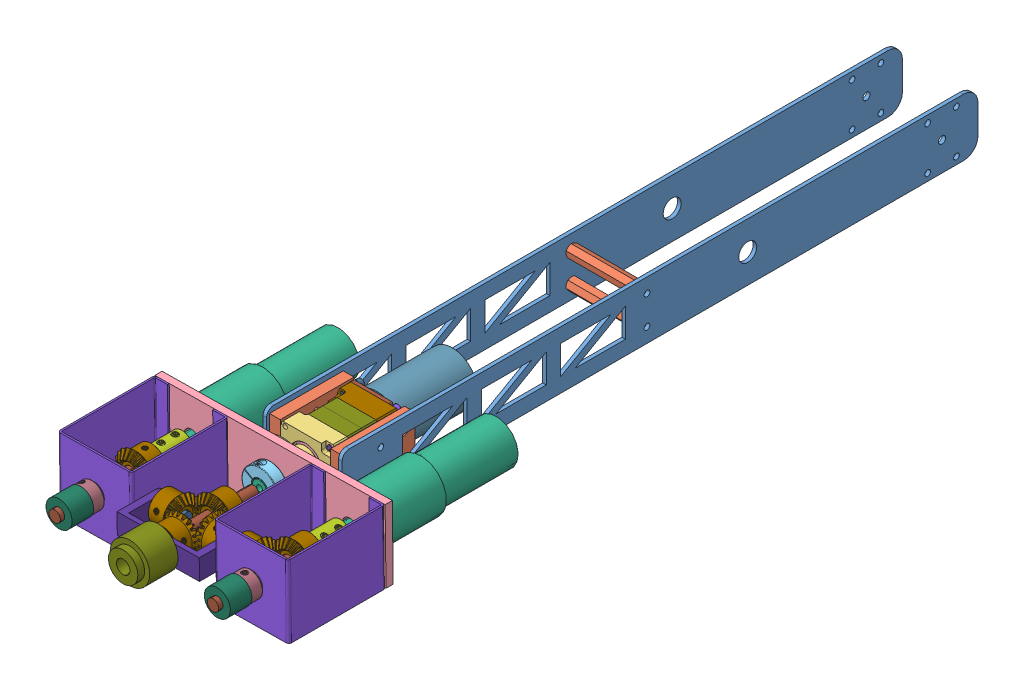
SolidWorks assembly Wrist, configuration Default. Lengths in mm.
Overall size (204.05 66.26 719.42).
77 component instances, 35 part files, 98 mates.
Components (placement in the parent):
- Arm_Plate-1: Arm_Plate [Default] at (186.0926 430.0867 393.4648) size (3.17 50.8 561.12)
- Arm_Plate-2: Arm_Plate [Default] at (252.7676 430.0867 393.4648) size (3.17 50.8 561.12)
- Beta_Standoff-1: Beta_Standoff [91115A862] at (221.0176 442.7867 507.7648) x (0 -0.986565 -0.163369) z (-1 0 0) size (9.53 11 64.12)
- Beta_Standoff-2: Beta_Standoff [91115A862] at (221.0176 468.1867 507.7648) x (0 0.925164 -0.379567) z (-1 0 0) size (9.53 11 64.12)
- Gearbox-1: Gearbox [Default] at (243.2426 455.4867 757.6023) x (0 0 1) z (0 -1 0) size (107.66 49.05 49.3)
  - 217-2625-026 Rev1-1: 217-2625-026 Rev1 [Default] at (-6.5 22.225 0) x (0 -1 0) z (-1 0 0) size (44.45 42 18.13)
  - 217-2742-001 Rev4-1: 217-2742-001 Rev4 [Default] at (0.2002 22.225 0) x (1 0 0) z (0 -0.092627 0.995701) size (7 28 28)
  - 217-2742-001 Rev4-2: 217-2742-001 Rev4 [Default] at (8.2002 22.225 0) size (7 28 28)
  - 217-2625-017 Rev1_9714K61-1: 217-2625-017 Rev1_9714K61 [Default] at (7.42 22.3002 -0.342) x (0 0.56703 0.823697) z (0 -0.823697 0.56703) size (28.51 4.98 30.18)
  - 217-2625-003 Rev1-1: 217-2625-003 Rev1 [Default] at (7.4478 22.225 0) x (0 -1 0) z (1 0 0) size (17 17 64.12)
  - 217-2625-018 Rev1_98541A410-1: 217-2625-018 Rev1_98541A410 [Default] at (-0.7046 22.225 0) x (1 0 0) z (0 -0.017452 0.999848) size (1 19.6 17.4)
  - 832-2250-Base-Kit-Screw_SSA0832-0500ZC-1: 832-2250-Base-Kit-Screw_SSA0832-0500ZC [Default] at (-43.4 4.725 -17.5) x (0 -0.767799 -0.640691) z (0 0.640691 -0.767799) size (6.73 61.21 6.73)
  - 832-2250-Base-Kit-Screw_SSA0832-0500ZC-2: 832-2250-Base-Kit-Screw_SSA0832-0500ZC [Default] at (-43.4 39.725 17.5) x (0 0.961307 0.275478) z (0 -0.275478 0.961307) size (6.73 61.21 6.73)
  - 217-2625-025 Rev1-1: 217-2625-025 Rev1 [Default] at (-35.9 22.225 0) x (0 -1 0) z (-1 0 0) size (44.45 42 18)
  - 217-4649-002 Rev1_SSA0832-0500ZC-1: 217-4649-002 Rev1_SSA0832-0500ZC [Default] at (-46.4 4.2645 17.9605) x (0 0.33842 -0.940995) z (0 0.940995 0.33842) size (6.73 16.76 6.73)
  - 217-4649-002 Rev1_SSA0832-0500ZC-2: 217-4649-002 Rev1_SSA0832-0500ZC [Default] at (-46.4 40.1855 -17.9605) x (0 -0.308932 -0.951084) z (0 0.951084 -0.308932) size (6.73 16.76 6.73)
  - 217-2822-003 Rev4-1: 217-2822-003 Rev4 [Default] at (-44.9 22.225 0) x (0 -1 0) z (-1 0 0) size (42 42 4.8)
  - 217-2820 Rev1_Public-1: 217-2820 Rev1_Public [Default] at (-4.6546 22.225 0) x (0 -0.456494 0.889726) z (-1 0 0) size (39.26 38.9 17.4)
    - 217-2625-100-1: 217-2625-100 [Default] at origin size (39.26 38.9 12.7)
      - 217-2625-008 Rev1-1: 217-2625-008 Rev1 [Default] at origin size (34.7 34.7 4.7)
      - 217-2625-010 Rev1-1: 217-2625-010 Rev1 [Default] at (0 10.193 3.65) x (0.999813 0.019336 0) z (0 0 1) size (4 4 12)
      - 217-2625-010 Rev1-2: 217-2625-010 Rev1 [Default] at (8.691 -5.3258 3.65) size (4 4 12)
      - 217-2625-010 Rev1-3: 217-2625-010 Rev1 [Default] at (-8.691 -5.3258 3.65) size (4 4 12)
      - 217-2625-005 Rev1_Planet_Revolving_Follower01-1: 217-2625-005 Rev1_Planet_Revolving_Follower01 [Default] at (8.691 -5.3258 6.35) x (0.932816 0.360354 0) z (0 0 1) size (16.91 16.92 8)
      - 217-2625-005 Rev1_Planet_Revolving_Follower01-2: 217-2625-005 Rev1_Planet_Revolving_Follower01 [Default] at (-8.691 -5.3258 6.35) x (-0.932788 -0.360426 0) z (0 0 1) size (16.91 16.92 8)
      - 217-2625-005 Rev1_Planet_Revolving_Follower01-3: 217-2625-005 Rev1_Planet_Revolving_Follower01 [Default] at (0 10.193 6.35) x (0.893583 0.448898 0) z (0 0 1) size (16.91 16.92 8)
    - 217-2625-007 Rev1_Public-1: 217-2625-007 Rev1_Public [Default] at (0 0 6.7) x (0.992772 0.120019 0) z (0 0 1) size (14.49 14.49 12.72)
  - 217-2816-001 Rev1-1: 217-2816-001 Rev1 [Default] at (-6.35 22.225 0) x (0 -1 0) z (1 0 0) size (42 42 14.5)
  - 217-2820 Rev1_Public-2: 217-2820 Rev1_Public [Default] at (-17.15 22.225 0) x (0 0.184082 0.982911) z (-1 0 0) size (39.26 38.9 17.4)
    - 217-2625-100-1: 217-2625-100 [Default] at origin size (39.26 38.9 12.7)
      - 217-2625-008 Rev1-1: 217-2625-008 Rev1 [Default] at origin size (34.7 34.7 4.7)
      - 217-2625-010 Rev1-1: 217-2625-010 Rev1 [Default] at (0 10.193 3.65) x (0.999813 0.019336 0) z (0 0 1) size (4 4 12)
      - 217-2625-010 Rev1-2: 217-2625-010 Rev1 [Default] at (8.691 -5.3258 3.65) size (4 4 12)
      - 217-2625-010 Rev1-3: 217-2625-010 Rev1 [Default] at (-8.691 -5.3258 3.65) size (4 4 12)
      - 217-2625-005 Rev1_Planet_Revolving_Follower01-1: 217-2625-005 Rev1_Planet_Revolving_Follower01 [Default] at (8.691 -5.3258 6.35) x (0.932816 0.360354 0) z (0 0 1) size (16.91 16.92 8)
      - 217-2625-005 Rev1_Planet_Revolving_Follower01-2: 217-2625-005 Rev1_Planet_Revolving_Follower01 [Default] at (-8.691 -5.3258 6.35) x (-0.932788 -0.360426 0) z (0 0 1) size (16.91 16.92 8)
      - 217-2625-005 Rev1_Planet_Revolving_Follower01-3: 217-2625-005 Rev1_Planet_Revolving_Follower01 [Default] at (0 10.193 6.35) x (0.893583 0.448898 0) z (0 0 1) size (16.91 16.92 8)
    - 217-2625-007 Rev1_Public-1: 217-2625-007 Rev1_Public [Default] at (0 0 6.7) x (0.992772 0.120019 0) z (0 0 1) size (14.49 14.49 12.72)
  - 217-2816-001 Rev1-2: 217-2816-001 Rev1 [Default] at (-19.05 22.225 0) x (0 -1 0) z (1 0 0) size (42 42 14.5)
  - 217-4649-001 Rev1-1: 217-4649-001 Rev1 [Default] at (-32.746 22.225 0) x (0 -1 0) z (1 0 0) size (18 18 13)
  - 217-4649-007 Rev1_94105A824-1: 217-4649-007 Rev1_94105A824 [Default] at (-38.221 22.225 -6.7835) x (-0.996104 -0.088191 0) z (0 0 -1) size (4.83 4.83 4.9)
  - 217-2625-011 Rev1-1: 217-2625-011 Rev1 [Default] at (-37.4818 22.225 0) x (0 0 1) z (0 -1 0) size (8.01 7.5 7.94)
- Standoff_Plate-1: Standoff_Plate [Default] at (198.7926 476.4867 709.1173) x (0 0 -1) z (0 1 0) size (65.11 9.53 42)
- Standoff_Plate-2: Standoff_Plate [Default] at (243.2426 434.4867 709.1173) x (0 0 -1) z (0 -1 0) size (65.11 9.53 42)
- Hex_Hub-1: Hex_Hub [Default] at (220.9668 455.4867 780.2423) x (0 0 -1) z (-1 0 0) size (25.4 57.15 57.15)
- Fork-2: Fork [Default] at (119.8085 422.3563 805.0883) x (-0.999907 -0.013615 0) z (0.013615 -0.999907 0) size (203.2 6.35 63.5)
- Hex_Collar-1: Hex_Collar [7552K5] at (220.9668 455.4867 809.8508) x (-0.5 -0.866025 0) z (0 0 -1) size (31.75 31.77 10.99)
- PG71-3: PG71 [Default] at (151.1233 454.5357 742.2233) x (0.829348 0.558732 0) z (0.558732 -0.829348 0) size (45.01 149.99 45.01)
- PG71-4: PG71 [Default] at (290.8104 456.4377 742.2233) x (0.30986 0.950782 0) z (0.950782 -0.30986 0) size (45.01 149.99 45.01)
- 10mm_Coupler-1: 10mm_Coupler [5395T312] at (290.8104 456.4377 825.6623) x (0.860413 -0.509597 0) z (0 0 1) size (19 20.01 25.02)
- 10mm_Coupler-2: 10mm_Coupler [5395T312] at (151.1233 454.5357 825.6623) size (19 20.01 25.02)
- Differential_Plate-3: Differential_Plate [Default] at (259.2456 424.2549 806.6758) x (-0.999907 -0.013615 0) z (-0.013615 0.999907 0) size (65.34 85.73 63.5)
- Differential_Plate-4: Differential_Plate [Default] at (182.6881 486.7184 806.6758) x (0.999907 0.013615 0) z (0.013615 -0.999907 0) size (65.34 85.73 63.5)
- Miter-7: Miter [2600N3] at (151.1233 454.5357 855.0883) x (-0.049068 -0.998795 0) z (-0.998795 0.049068 0) size (31.74 21.31 31.74)
- Miter-8: Miter [2600N3] at (290.8104 456.4377 855.0883) x (0.920442 -0.390878 0) z (-0.390878 -0.920442 0) size (31.74 21.31 31.74)
- Miter-9: Miter [2600N3] at (166.1219 454.7399 870.0883) x (-0.002712 0.199199 -0.979955) z (-0.013342 0.979865 0.199217) size (31.74 21.31 31.74)
- Miter-10: Miter [2600N3] at (275.8117 456.2335 870.0883) x (0.010216 -0.750274 -0.661048) z (0.009 -0.660987 0.750343) size (31.74 21.31 31.74)
- 10mm_Shaft-7: 10mm_Shaft [Default] at (212.1176 455.3662 870.0883) x (-0.001745 0.128178 -0.99175) z (-0.013503 0.991658 0.12819) size (10 50 10)
- 10mm_Shaft-8: 10mm_Shaft [Default] at (279.8114 456.2879 870.0883) x (0.007901 -0.580251 -0.814399) z (-0.011088 0.814324 -0.580305) size (10 50 10)
- Miter-11: Miter [2600N3] at (235.9654 455.6909 870.0883) x (0.012189 -0.895158 -0.445582) z (-0.006067 0.44554 -0.895241) size (31.74 21.31 31.74)
- Miter-12: Miter [2600N3] at (205.9682 455.2824 870.0883) x (0.00474 -0.348103 -0.937444) z (0.012763 -0.937358 0.348135) size (31.74 21.31 31.74)
- Pitch_Shaft-10: Pitch_Shaft [Default] at (290.8104 456.4377 925.6623) x (-0.350616 -0.936519 0) z (0.936519 -0.350616 0) size (10 100 10)
- 10mm_Bearing-1: 10mm_Bearing [Default] at (290.8104 456.4377 892.8133) x (-0.923728 -0.383049 0) z (0.383049 -0.923728 0) size (18 8 18)
- 10mm_Collar-1: 10mm_Collar [57485K68] at (290.8104 456.4377 892.8133) size (22 22 10)
- Pitch_Shaft-11: Pitch_Shaft [Default] at (151.1233 454.5357 925.6623) x (-0.160979 -0.986958 0) z (0.986958 -0.160979 0) size (10 100 10)
- 10mm_Bearing-2: 10mm_Bearing [Default] at (151.1233 454.5357 892.8133) x (-0.561775 -0.82729 0) z (0.82729 -0.561775 0) size (18 8 18)
- 10mm_Collar-2: 10mm_Collar [57485K68] at (151.1233 454.5357 892.8133) x (0.924433 0.381344 0) z (0 0 1) size (22 22 10)
- 10mm_Bearing-3: 10mm_Bearing [Default] at (260.8131 456.0292 870.0883) x (0.013072 -0.960036 0.279573) z (0.003806 -0.279547 -0.960124) size (18 8 18)
- 10mm_Bearing-4: 10mm_Bearing [Default] at (181.1205 454.9441 870.0883) x (0.002168 -0.159219 0.987241) z (-0.013441 0.987149 0.159233) size (18 8 18)
- Pitch_Shaft-14: Pitch_Shaft [Default] at (220.9668 455.4867 920.0883) x (0.474138 -0.880451 0) z (0.880451 0.474138 0) size (10 100 10)
- Miter-19: Miter [2600N3] at (220.9668 455.4867 885.0883) x (-0.926792 -0.375575 0) z (0.375575 -0.926792 0) size (31.74 21.31 31.74)
- Miter-20: Miter [2600N3] at (220.9668 455.4867 855.0883) x (-0.987805 -0.155698 0) z (-0.155698 0.987805 0) size (31.74 21.31 31.74)
- 9015_Motor-1: 9015_Motor [Default] at (221.0176 455.4867 711.2023) x (0.980858 0.194723 0) z (-0.194723 0.980858 0) size (44.5 66.55 44.5)
- Encoder-1: Encoder [Default] at (290.8104 456.4377 902.8133) x (0.92907 -0.369904 0) z (-0.369904 -0.92907 0) size (23 19 23)
- Encoder-2: Encoder [Default] at (151.1233 454.5357 902.8133) x (0.974433 -0.224677 0) z (-0.224677 -0.974433 0) size (23 19 23)
- Slip_Ring-2: Slip_Ring [Default] at (220.9668 455.4867 904.0883) x (-0.999021 -0.044228 0) z (-0.044228 0.999021 0) size (35 31 35)
- Differential_Cover-1: Differential_Cover [Default] at (190.9696 455.0782 870.0883) x (-0.999907 -0.013615 0) z (0.013615 -0.999907 0) size (72.52 43 18)
Mates (geometry in assembly coordinates):
- Coincident1: coincident anti-aligned: plane of Arm_Plate-1 through (189.2676 442.7867 228.3648) normal (1 0 0); plane of Beta_Standoff-1 through (189.2676 441.8883 513.1902) normal (-1 0 0)
- Coincident2: coincident anti-aligned: plane of Arm_Plate-2 through (252.7676 442.7867 228.3648) normal (-1 0 0); plane of Beta_Standoff-1 through (252.7676 441.8883 513.1902) normal (1 0 0)
- Concentric1: concentric aligned: circle of Arm_Plate-1; circle of Beta_Standoff-1
- Concentric2: concentric aligned: circle of Arm_Plate-1; circle of Arm_Plate-2
- Concentric3: concentric aligned: circle of Arm_Plate-1; circle of Beta_Standoff-2
- Coincident4: coincident anti-aligned: plane of Arm_Plate-1 through (189.2676 442.7867 228.3648) normal (1 0 0); plane of Beta_Standoff-2 through (189.2676 466.0994 502.6771) normal (-1 0 0)
- Parallel1: parallel anti-aligned: plane of Arm_Plate-2 through (255.9426 442.7867 228.3648) normal (1 0 0); plane of Gearbox-1/217-2816-001 Rev1-1 through (200.0176 434.4867 757.6023) normal (-1 0 0)
- Parallel2: parallel aligned: plane of Arm_Plate-2 through (255.9426 480.8867 228.3648) normal (0 1 0); plane of Gearbox-1/217-2625-026 Rev1-1 through (242.0176 476.4867 756.1023) normal (0 1 0)
- Width2: width anti-aligned: plane of Arm_Plate-2 through (255.9426 442.7867 228.3648) normal (1 0 0); plane of Arm_Plate-1 through (186.0926 442.7867 228.3648) normal (-1 0 0); plane of Gearbox-1/217-2816-001 Rev1-1 through (200.0176 434.4867 757.6023) normal (-1 0 0); plane of Gearbox-1/217-2816-001 Rev1-1 through (242.0176 434.4867 757.6023) normal (1 0 0)
- Width3: width anti-aligned: plane of Arm_Plate-2 through (255.9426 480.8867 228.3648) normal (0 1 0); plane of Arm_Plate-2 through (255.9426 430.0867 228.3648) normal (0 -1 0); plane of Gearbox-1/217-2816-001 Rev1-2 through (200.0176 434.4867 744.9023) normal (0 -1 0); plane of Gearbox-1/217-2816-001 Rev1-2 through (200.0176 476.4867 744.9023) normal (0 1 0)
- Concentric4: concentric aligned: circle of Arm_Plate-1; circle of Arm_Plate-2
- Width4: width: plane of Gearbox-1/217-2822-003 Rev4-1 through (221.0176 455.4867 711.2023) normal (0 0 -1); plane of Gearbox-1/217-2625-026 Rev1-1 through (198.7926 433.2617 774.2273) normal (0 0 1); cylinder of Arm_Plate-2 through (255.9426 442.7867 742.7148) axis (-1 0 0) radius 2.5527
- Coincident9: coincident anti-aligned: plane of Gearbox-1/217-2625-026 Rev1-1 through (198.7926 477.7117 774.2273) normal (-1 0 0); plane of Standoff_Plate-1 through (198.7926 476.4867 709.1173) normal (1 0 0)
- Coincident10: coincident aligned: plane of Gearbox-1/217-2625-026 Rev1-1 through (198.7926 433.2617 774.2273) normal (0 0 1); plane of Standoff_Plate-1 through (189.2676 476.4867 774.2273) normal (0 0 1)
- Coincident11: coincident aligned: plane of Gearbox-1/217-2625-026 Rev1-1 through (242.0176 434.4867 756.1023) normal (0 -1 0); plane of Standoff_Plate-1 through (189.2676 434.4867 709.1173) normal (0 -1 0)
- Coincident12: coincident anti-aligned: plane of Gearbox-1/217-2625-026 Rev1-1 through (243.2426 477.7117 774.2273) normal (1 0 0); plane of Standoff_Plate-2 through (243.2426 434.4867 709.1173) normal (-1 0 0)
- Coincident14: coincident aligned: plane of Gearbox-1/217-2625-026 Rev1-1 through (198.7926 433.2617 774.2273) normal (0 0 1); plane of Standoff_Plate-2 through (252.7676 434.4867 774.2273) normal (0 0 1)
- Coincident15: coincident aligned: plane of Gearbox-1/217-2625-026 Rev1-1 through (242.0176 476.4867 756.1023) normal (0 1 0); plane of Standoff_Plate-2 through (252.7676 476.4867 709.1173) normal (0 1 0)
- Coincident16: coincident anti-aligned: plane of Gearbox-1/217-2625-003 Rev1-1 through (221.0176 448.1543 814.8025) normal (0.5 -0.866025 0); plane of Hex_Hub-1 through (220.9668 448.125 774.2273) normal (-0.5 0.866025 0)
- Coincident17: coincident anti-aligned: plane of Gearbox-1/217-2625-026 Rev1-1 through (198.7926 433.2617 774.2273) normal (0 0 1); plane of Hex_Hub-1 through (220.9668 455.4867 774.2273) normal (0 0 -1)
- Coincident18: coincident anti-aligned: plane of Gearbox-1/217-2625-003 Rev1-1 through (227.3676 459.1529 814.8025) normal (0.5 0.866025 0); plane of Hex_Hub-1 through (227.3422 459.1675 774.2273) normal (-0.5 -0.866025 0)
- Coincident21: coincident anti-aligned: plane of Hex_Hub-1 through (220.9668 455.4867 798.7383) normal (0 0 1); plane of Fork-2 through (119.8085 422.3563 798.7383) normal (0 0 -1)
- Concentric7: concentric aligned: circle of Hex_Hub-1; cylinder of Fork-2 through (220.9668 455.4867 805.0883) axis (0 0 -1) radius 6.35
- Coincident22: coincident anti-aligned: plane of Fork-2 through (119.8085 422.3563 805.0883) normal (0 0 1); plane of Hex_Collar-1 through (220.9668 455.4867 805.0883) normal (0 0 -1)
- Concentric8: concentric aligned: cylinder of Hex_Hub-1 through (220.9668 455.4867 774.2273) axis (0 0 1) radius 12.1666; cylinder of Hex_Collar-1 through (220.9668 455.4867 805.0883) axis (0 0 1) radius 15.875
- Parallel4: parallel anti-aligned: plane of Gearbox-1/217-2625-003 Rev1-1 through (214.6676 451.8205 814.8025) normal (-0.5 -0.866025 0); plane of Hex_Collar-1 through (220.9668 448.1543 805.0883) normal (0.5 0.866025 0)
- Coincident25: coincident anti-aligned: plane of Fork-2 through (119.8085 422.3563 798.7383) normal (0 0 -1); plane of PG71-3 through (151.1233 454.5357 798.7383) normal (0 0 1)
- Coincident26: coincident anti-aligned: plane of Fork-2 through (119.8085 422.3563 798.7383) normal (0 0 -1); plane of PG71-4 through (290.8104 456.4377 798.7383) normal (0 0 1)
- Concentric10: concentric aligned: cylinder of Fork-2 through (151.1233 454.5357 805.0883) axis (0 0 -1) radius 6.35; cylinder of PG71-3 through (151.1233 454.5357 825.6623) axis (0 0 -1) radius 5
- Concentric11: concentric aligned: cylinder of Fork-2 through (290.8104 456.4377 805.0883) axis (0 0 -1) radius 6.35; cylinder of PG71-4 through (290.8104 456.4377 825.6623) axis (0 0 -1) radius 5
- Concentric25: concentric aligned: cylinder of PG71-4 through (290.8104 456.4377 825.6623) axis (0 0 -1) radius 5; cylinder of 10mm_Coupler-1 through (290.8104 456.4377 838.1623) axis (0 0 -1) radius 5
- Concentric26: concentric aligned: cylinder of PG71-3 through (151.1233 454.5357 825.6623) axis (0 0 -1) radius 5; cylinder of 10mm_Coupler-2 through (151.1233 454.5357 838.1623) axis (0 0 -1) radius 5
- Distance7: distance = 12.5 mm aligned: plane of 10mm_Coupler-1 through (290.8104 456.4377 838.1623) normal (0 0 1); plane of PG71-4 through (290.8104 456.4377 825.6623) normal (0 0 1)
- Distance8: distance = 12.5 mm aligned: plane of 10mm_Coupler-2 through (151.1233 454.5357 838.1623) normal (0 0 1); plane of PG71-3 through (151.1233 454.5357 825.6623) normal (0 0 1)
- Coincident41: coincident anti-aligned: plane of Fork-2 through (119.8085 422.3563 805.0883) normal (0 0 1); plane of Differential_Plate-3 through (259.2456 424.2549 805.0883) normal (0 0 -1)
- Coincident42: coincident anti-aligned: plane of Fork-2 through (119.8085 422.3563 805.0883) normal (0 0 1); plane of Differential_Plate-4 through (182.6881 486.7184 805.0883) normal (0 0 -1)
- Parallel9: parallel anti-aligned: plane of Fork-2 through (119.8085 422.3563 798.7383) normal (-0.999907 -0.013615 0); plane of Differential_Plate-3 through (258.381 487.7491 806.6758) normal (0.999907 0.013615 0)
- Parallel10: parallel aligned: plane of Fork-2 through (119.8085 422.3563 798.7383) normal (-0.999907 -0.013615 0); plane of Differential_Plate-4 through (183.5526 423.2243 806.6758) normal (-0.999907 -0.013615 0)
- Coincident43: coincident aligned: plane of Fork-2 through (119.8085 422.3563 798.7383) normal (0.013615 -0.999907 0); plane of Differential_Plate-4 through (172.4411 423.073 805.0883) normal (0.013615 -0.999907 0)
- Coincident44: coincident aligned: plane of Fork-2 through (119.8085 422.3563 798.7383) normal (0.013615 -0.999907 0); plane of Differential_Plate-3 through (259.2456 424.2549 805.0883) normal (0.013615 -0.999907 0)
- Distance11: distance = 35 mm anti-aligned: plane of Miter-7 through (151.1233 454.5357 840.0883) normal (0 0 -1); plane of Fork-2 through (119.8085 422.3563 805.0883) normal (0 0 1)
- Distance12: distance = 35 mm anti-aligned: plane of Miter-8 through (290.8104 456.4377 840.0883) normal (0 0 -1); plane of Fork-2 through (119.8085 422.3563 805.0883) normal (0 0 1)
- Concentric33: concentric aligned: circle of Differential_Plate-4; cylinder of Miter-9 through (146.5963 454.474 870.0883) axis (-0.999907 -0.013615 0) radius 5
- Concentric34: concentric aligned: circle of Differential_Plate-3; cylinder of Miter-10 through (295.3374 456.4993 870.0883) axis (0.999907 0.013615 0) radius 5
- GearMate5: gear = 26 : 26 mm: cylinder of Miter-7 through (151.1233 454.5357 871.5883) axis (0 0 -1) radius 13; cylinder of Miter-9 through (149.6234 454.5152 870.0883) axis (0.999907 0.013615 0) radius 13
- GearMate6: gear = 26 : 26 mm: cylinder of Miter-10 through (292.3102 456.4581 870.0883) axis (-0.999907 -0.013615 0) radius 13; cylinder of Miter-8 through (290.8104 456.4377 871.5883) axis (0 0 -1) radius 13
- Concentric35: concentric anti-aligned: cylinder of Miter-9 through (146.5963 454.474 870.0883) axis (-0.999907 -0.013615 0) radius 5; cylinder of 10mm_Shaft-7 through (162.1223 454.6854 870.0883) axis (0.999907 0.013615 0) radius 5
- Concentric36: concentric aligned: cylinder of Miter-10 through (295.3374 456.4993 870.0883) axis (0.999907 0.013615 0) radius 5; cylinder of 10mm_Shaft-8 through (229.816 455.6072 870.0883) axis (0.999907 0.013615 0) radius 5
- Coincident47: coincident aligned: plane of Miter-10 through (279.8114 456.2879 870.0883) normal (0.999907 0.013615 0); plane of 10mm_Shaft-8 through (279.8114 456.2879 870.0883) normal (0.999907 0.013615 0)
- Coincident48: coincident aligned: plane of Miter-9 through (162.1223 454.6854 870.0883) normal (-0.999907 -0.013615 0); plane of 10mm_Shaft-7 through (162.1223 454.6854 870.0883) normal (-0.999907 -0.013615 0)
- Concentric37: concentric aligned: cylinder of 10mm_Shaft-7 through (162.1223 454.6854 870.0883) axis (0.999907 0.013615 0) radius 5; cylinder of Miter-12 through (225.4939 455.5483 870.0883) axis (0.999907 0.013615 0) radius 5
- Concentric38: concentric anti-aligned: cylinder of 10mm_Shaft-8 through (229.816 455.6072 870.0883) axis (0.999907 0.013615 0) radius 5; cylinder of Miter-11 through (216.4398 455.425 870.0883) axis (-0.999907 -0.013615 0) radius 5
- Distance13: distance = 60 mm anti-aligned: plane of Miter-12 through (190.9696 455.0782 870.0883) normal (-0.999907 -0.013615 0); plane of Miter-11 through (250.964 455.8951 870.0883) normal (0.999907 0.013615 0)
- Width10: width aligned: plane of Differential_Plate-4 through (185.14 423.2459 806.6758) normal (0.999907 0.013615 0); plane of Differential_Plate-3 through (256.7937 487.7274 806.6758) normal (-0.999907 -0.013615 0); plane of Miter-11 through (250.964 455.8951 870.0883) normal (0.999907 0.013615 0); plane of Miter-12 through (190.9696 455.0782 870.0883) normal (-0.999907 -0.013615 0)
- GearMate7: gear = 26 : 26 mm: cylinder of Miter-12 through (222.4667 455.5071 870.0883) axis (-0.999907 -0.013615 0) radius 13; cylinder of Miter-9 through (149.6234 454.5152 870.0883) axis (0.999907 0.013615 0) radius 13
- GearMate8: gear = 26 : 26 mm: cylinder of Miter-11 through (219.467 455.4662 870.0883) axis (0.999907 0.013615 0) radius 13; cylinder of Miter-10 through (292.3102 456.4581 870.0883) axis (-0.999907 -0.013615 0) radius 13
- Concentric39: concentric anti-aligned: cylinder of 10mm_Coupler-1 through (290.8104 456.4377 838.1623) axis (0 0 -1) radius 5; cylinder of Miter-8 through (290.8104 456.4377 874.6158) axis (0 0 1) radius 5
- Concentric40: concentric anti-aligned: cylinder of 10mm_Coupler-1 through (290.8104 456.4377 838.1623) axis (0 0 -1) radius 9.5; cylinder of Pitch_Shaft-10 through (290.8104 456.4377 825.6623) axis (0 0 1) radius 5
- Coincident49: coincident anti-aligned: plane of PG71-4 through (290.8104 456.4377 825.6623) normal (0 0 1); plane of Pitch_Shaft-10 through (290.8104 456.4377 825.6623) normal (0 0 -1)
- Concentric41: concentric aligned: cylinder of Pitch_Shaft-10 through (290.8104 456.4377 825.6623) axis (0 0 1) radius 5; cylinder of 10mm_Bearing-1 through (290.8104 456.4377 884.8133) axis (0 0 1) radius 7
- Coincident50: coincident anti-aligned: plane of Differential_Plate-3 through (259.2456 424.2549 890.8133) normal (0 0 1); plane of 10mm_Bearing-1 through (290.8104 456.4377 890.8133) normal (0 0 -1)
- Concentric42: concentric anti-aligned: cylinder of Pitch_Shaft-10 through (290.8104 456.4377 825.6623) axis (0 0 1) radius 5; cylinder of 10mm_Collar-1 through (290.8104 456.4377 902.8133) axis (0 0 -1) radius 5
- Coincident51: coincident anti-aligned: plane of 10mm_Bearing-1 through (290.8104 456.4377 892.8133) normal (0 0 1); plane of 10mm_Collar-1 through (290.8104 456.4377 892.8133) normal (0 0 -1)
- Concentric43: concentric aligned: cylinder of 10mm_Coupler-2 through (151.1233 454.5357 838.1623) axis (0 0 -1) radius 9.5; cylinder of Miter-7 through (151.1233 454.5357 871.5883) axis (0 0 -1) radius 13
- Concentric44: concentric anti-aligned: cylinder of 10mm_Coupler-2 through (151.1233 454.5357 838.1623) axis (0 0 -1) radius 9.5; cylinder of Pitch_Shaft-11 through (151.1233 454.5357 825.6623) axis (0 0 1) radius 5
- Coincident52: coincident anti-aligned: plane of PG71-3 through (151.1233 454.5357 825.6623) normal (0 0 1); plane of Pitch_Shaft-11 through (151.1233 454.5357 825.6623) normal (0 0 -1)
- Concentric45: concentric aligned: cylinder of Pitch_Shaft-11 through (151.1233 454.5357 825.6623) axis (0 0 1) radius 5; cylinder of 10mm_Bearing-2 through (151.1233 454.5357 884.8133) axis (0 0 1) radius 7
- Coincident53: coincident anti-aligned: plane of Differential_Plate-4 through (182.6881 486.7184 890.8133) normal (0 0 1); plane of 10mm_Bearing-2 through (151.1233 454.5357 890.8133) normal (0 0 -1)
- Concentric46: concentric anti-aligned: cylinder of Pitch_Shaft-11 through (151.1233 454.5357 825.6623) axis (0 0 1) radius 5; cylinder of 10mm_Collar-2 through (151.1233 454.5357 902.8133) axis (0 0 -1) radius 5
- Coincident54: coincident anti-aligned: plane of 10mm_Bearing-2 through (151.1233 454.5357 892.8133) normal (0 0 1); plane of 10mm_Collar-2 through (151.1233 454.5357 892.8133) normal (0 0 -1)
- Coincident55: coincident aligned: plane of Fork-2 through (322.9897 425.1229 798.7383) normal (0.999907 0.013615 0); plane of Differential_Plate-3 through (322.9897 425.1229 806.6758) normal (0.999907 0.013615 0)
- Coincident56: coincident aligned: plane of Fork-2 through (119.8085 422.3563 798.7383) normal (-0.999907 -0.013615 0); plane of Differential_Plate-4 through (118.944 485.8504 806.6758) normal (-0.999907 -0.013615 0)
- Coincident58: coincident anti-aligned: plane of Miter-10 through (260.8131 456.0292 870.0883) normal (-0.999907 -0.013615 0); plane of 10mm_Bearing-3 through (260.8131 456.0292 870.0883) normal (0.999907 0.013615 0)
- Concentric48: concentric anti-aligned: cylinder of 10mm_Shaft-7 through (162.1223 454.6854 870.0883) axis (0.999907 0.013615 0) radius 5; cylinder of 10mm_Bearing-4 through (183.1203 454.9713 870.0883) axis (-0.999907 -0.013615 0) radius 5
- Coincident59: coincident anti-aligned: plane of Differential_Plate-4 through (183.5526 423.2243 806.6758) normal (-0.999907 -0.013615 0); plane of 10mm_Bearing-4 through (183.1203 454.9713 870.0883) normal (0.999907 0.013615 0)
- Coincident60: coincident anti-aligned: plane of Miter-9 through (181.1205 454.9441 870.0883) normal (0.999907 0.013615 0); plane of 10mm_Bearing-4 through (181.1205 454.9441 870.0883) normal (-0.999907 -0.013615 0)
- Concentric51: concentric aligned: cylinder of 10mm_Shaft-8 through (229.816 455.6072 870.0883) axis (0.999907 0.013615 0) radius 5; cylinder of 10mm_Bearing-3 through (258.8133 456.002 870.0883) axis (0.999907 0.013615 0) radius 5
- Coincident62: coincident anti-aligned: plane of Differential_Plate-3 through (258.381 487.7491 806.6758) normal (0.999907 0.013615 0); plane of 10mm_Bearing-3 through (258.8133 456.002 870.0883) normal (-0.999907 -0.013615 0)
- Concentric52: concentric aligned: cylinder of Pitch_Shaft-14 through (220.9668 455.4867 820.0883) axis (0 0 1) radius 5; cylinder of Miter-19 through (220.9668 455.4867 868.5883) axis (0 0 1) radius 13
- Concentric53: concentric anti-aligned: cylinder of Pitch_Shaft-14 through (220.9668 455.4867 820.0883) axis (0 0 1) radius 5; cylinder of Miter-20 through (220.9668 455.4867 871.5883) axis (0 0 -1) radius 13
- Distance14: distance = 60 mm anti-aligned: plane of Miter-20 through (220.9668 455.4867 840.0883) normal (0 0 -1); plane of Miter-19 through (220.9668 455.4867 900.0883) normal (0 0 1)
- Width11: width anti-aligned: plane of Pitch_Shaft-14 through (220.9668 455.4867 920.0883) normal (0 0 1); plane of Pitch_Shaft-14 through (220.9668 455.4867 820.0883) normal (0 0 -1); plane of Miter-20 through (220.9668 455.4867 840.0883) normal (0 0 -1); plane of Miter-19 through (220.9668 455.4867 900.0883) normal (0 0 1)
- Width12: width: plane of Differential_Plate-3 through (256.7937 487.7274 806.6758) normal (-0.999907 -0.013615 0); plane of Differential_Plate-4 through (185.14 423.2459 806.6758) normal (0.999907 0.013615 0); cylinder of Pitch_Shaft-14 through (220.9668 455.4867 820.0883) axis (0 0 1) radius 5
- Width13: width: plane of Miter-20 through (220.9668 455.4867 840.0883) normal (0 0 -1); plane of Miter-19 through (220.9668 455.4867 900.0883) normal (0 0 1); cylinder of Miter-12 through (222.4667 455.5071 870.0883) axis (-0.999907 -0.013615 0) radius 13
- Width14: width: plane of Differential_Plate-3 through (259.2456 424.2549 806.6758) normal (0.013615 -0.999907 0); plane of Differential_Plate-3 through (322.1251 488.617 889.2258) normal (-0.013615 0.999907 0); cylinder of Pitch_Shaft-14 through (220.9668 455.4867 820.0883) axis (0 0 1) radius 5
- GearMate9: gear = 26 : 26 mm: cylinder of Miter-19 through (220.9668 455.4867 868.5883) axis (0 0 1) radius 13; cylinder of Miter-11 through (219.467 455.4662 870.0883) axis (0.999907 0.013615 0) radius 13
- GearMate10: gear = 26 : 26 mm: cylinder of Miter-20 through (220.9668 455.4867 871.5883) axis (0 0 -1) radius 13; cylinder of Miter-12 through (222.4667 455.5071 870.0883) axis (-0.999907 -0.013615 0) radius 13
- GearMate11: gear = 26 : 26 mm: cylinder of Miter-12 through (222.4667 455.5071 870.0883) axis (-0.999907 -0.013615 0) radius 13; cylinder of Miter-19 through (220.9668 455.4867 868.5883) axis (0 0 1) radius 13
- Concentric62: concentric anti-aligned: circle of Gearbox-1/217-2822-003 Rev4-1; cylinder of 9015_Motor-1 through (221.0176 455.4867 644.6543) axis (0 0 1) radius 22.2504
- Coincident70: coincident anti-aligned: plane of Gearbox-1/217-2822-003 Rev4-1 through (221.0176 455.4867 711.2023) normal (0 0 -1); plane of 9015_Motor-1 through (221.0176 455.4867 711.2023) normal (0 0 1)
- Concentric63: concentric anti-aligned: cylinder of Pitch_Shaft-10 through (290.8104 456.4377 825.6623) axis (0 0 1) radius 5; cylinder of Encoder-1 through (290.8104 456.4377 921.8133) axis (0 0 -1) radius 11.5
- Concentric64: concentric anti-aligned: cylinder of Pitch_Shaft-11 through (151.1233 454.5357 825.6623) axis (0 0 1) radius 5; cylinder of Encoder-2 through (151.1233 454.5357 921.8133) axis (0 0 -1) radius 11.5
- Coincident71: coincident anti-aligned: plane of 10mm_Collar-1 through (290.8104 456.4377 902.8133) normal (0 0 1); plane of Encoder-1 through (290.8104 456.4377 902.8133) normal (0 0 -1)
- Coincident72: coincident anti-aligned: plane of 10mm_Collar-2 through (151.1233 454.5357 902.8133) normal (0 0 1); plane of Encoder-2 through (151.1233 454.5357 902.8133) normal (0 0 -1)
- Concentric65: concentric aligned: cylinder of Pitch_Shaft-14 through (220.9668 455.4867 820.0883) axis (0 0 1) radius 5; cylinder of Slip_Ring-2 through (220.9668 455.4867 904.0883) axis (0 0 1) radius 6
- Concentric66: concentric anti-aligned: cylinder of 10mm_Bearing-4 through (189.1198 455.053 870.0883) axis (-0.999907 -0.013615 0) radius 7; cylinder of Differential_Cover-1 through (184.7102 454.993 870.0883) axis (0.999907 0.013615 0) radius 5
- Concentric67: concentric anti-aligned: cylinder of Pitch_Shaft-14 through (220.9668 455.4867 820.0883) axis (0 0 1) radius 5; cylinder of Differential_Cover-1 through (220.9668 455.4867 904.0883) axis (0 0 -1) radius 5
- Coincident73: coincident anti-aligned: plane of Slip_Ring-2 through (220.9668 455.4867 904.0883) normal (0 0 -1); plane of Differential_Cover-1 through (190.9696 455.0782 904.0883) normal (0 0 1)
